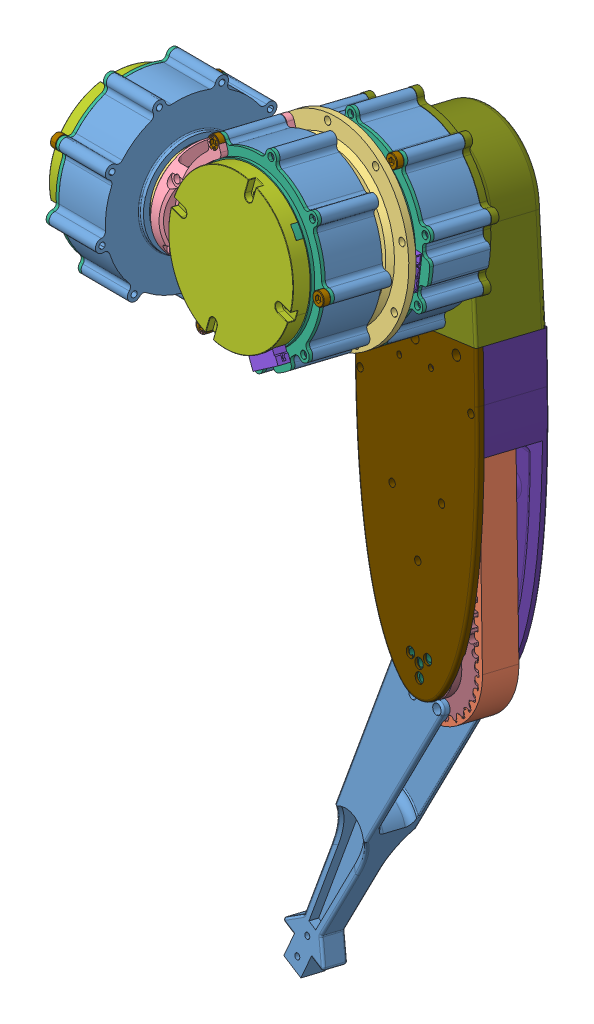
SolidWorks assembly 左后机械腿装配体, configuration 默认. Lengths in mm.
Overall size (159.19 372.62 150.59).
74 component instances, 22 part files, 38 mates.
Components (placement in the parent):
- CyberGearmotor.stp-1: CyberGearmotor.stp [默认] at (-142.9677 146.7561 185.5962) x (0.968253 -0.203796 0.14475) z (-0.114976 0.151089 0.981811) size (96.28 96.17 36.5)
  - ASM0002_ASM_1_ASM.stp-1: ASM0002_ASM_1_ASM.stp [默认] at origin size (96.28 96.17 36.5)
    - ASM0002_ASM_1_ASM_1_ASM.stp-1: ASM0002_ASM_1_ASM_1_ASM.stp [默认] at origin size (96.28 96.17 36.5)
      - 0714_ASM_1_ASM_1_ASM_1_ASM.stp-1: 0714_ASM_1_ASM_1_ASM_1_ASM.stp [默认] at origin size (96.28 96.17 36.5)
        - 3_1_02_067_0003_ASM_ASM_1_ASM_1_ASM.stp-1: 3_1_02_067_0003_ASM_ASM_1_ASM_1_ASM.stp [默认] at origin size (96.28 96.17 36.5)
          - 3_1_02_067_0003_ASM_1_ASM_1_ASM_ASM.stp-1: 3_1_02_067_0003_ASM_1_ASM_1_ASM_ASM.stp [默认] at origin size (96.28 96.17 36.5)
            - 1_1_06_EB673-504_1_1_1_1_1.stp-1: 1_1_06_EB673-504_1_1_1_1_1.stp [默认] at (39.8324 39.833 -22) size (79.19 78.95 25.5)
            - 1_2_04_670601_1_1_1_1_1.stp-1: 1_2_04_670601_1_1_1_1_1.stp [默认] at (93.9161 79.9966 -44) size (37 37 4)
            - 1_1_02_EB671-500_1_1_1_1_1.stp-1: 1_1_02_EB671-500_1_1_1_1_1.stp [默认] at (93.9161 79.9966 -44.4) x (-0.960973 0.276644 0) z (0 0 1) size (33 33 8.5)
            - 1_2_04_694000_1_1_1_1_1.stp-1: 1_2_04_694000_1_1_1_1_1.stp [默认] at (93.9161 79.9966 -44.5) size (11 11 4)
            - 1_2_06_000213_1_1_1_1_1.stp-1: 1_2_06_000213_1_1_1_1_1.stp [默认] at (93.9161 79.9966 -45.5) size (38.8 36.2 1.5)
            - 1_1_31_QT-642_1_1_1_1_1.stp-1: 1_1_31_QT-642_1_1_1_1_1.stp [默认] at (93.9161 79.9966 -22) x (-0.970555 -0.24088 0) z (0 0 -1) size (79.5 79.36 6)
            - 1_1_06_EB673-502_1_1_1_1_1.stp-1: 1_1_06_EB673-502_1_1_1_1_1.stp [默认] at (93.9161 79.9966 -13) x (-0.515958 -0.856614 0) z (0 0 -1) size (63 63 8)
          - 0518_ASM_2_ASM_1_ASM_1_ASM_1_AS_ASM.stp-1: 0518_ASM_2_ASM_1_ASM_1_ASM_1_AS_ASM.stp [默认] at (93.9161 79.9966 -17.235) x (0.235897 -0.971778 0) z (0 0 1) size (15.5 11.3 5.2)
            - 12345_ASM_1_ASM_2_ASM_1_ASM_1_A_ASM.stp-1: 12345_ASM_1_ASM_2_ASM_1_ASM_1_A_ASM.stp [默认] at origin size (15.5 11.3 5.2)
              - DUANZI_1_3_1_1_1_1_1_1.stp-1: DUANZI_1_3_1_1_1_1_1_1.stp [默认] at (-0.1798 16.5474 0.4329) x (0 0 -1) z (0 1 0) size (5.2 15.5 11.3)
      - LUODING_1_1.stp-1: LUODING_1_1.stp [默认] at (119.9375 52.9941 -20.5) x (-1 0 0) z (0 1 0) size (5.68 3 5.68)
      - LUODING_1_1.stp-2: LUODING_1_1.stp [默认] at (104.2902 116.0331 -20.5) x (-1 0 0) z (0 1 0) size (5.68 3 5.68)
      - LUODING_1_1.stp-3: LUODING_1_1.stp [默认] at (57.5205 70.9626 -20.5) x (-1 0 0) z (0 1 0) size (5.68 3 5.68)
  - 0411-2_4_1_3_1.stp-1: 0411-2_4_1_3_1.stp [默认] at (93.9161 79.9964 -17.5) x (0.235904 -0.971776 0) z (0 0 1) size (58 56.68 1.62)
- 带轮-1: 带轮 [默认] at (-26.5163 194.7974 123.0899) x (-0.682793 -0.729895 0.032363) z (-0.114976 0.151089 0.981811) size (43.22 43.22 15)
- 带轮挡边-1: 带轮挡边 [默认] at (-28.2409 197.0638 137.8171) x (-0.682793 -0.729895 0.032363) z (-0.114976 0.151089 0.981811) size (50 50 4)
- 带轮挡边-2: 带轮挡边 [默认] at (-26.0564 194.1931 119.1627) x (-0.432175 0.882318 -0.186388) z (-0.114976 0.151089 0.981811) size (50 50 4)
- 膝关节带轮-1: 膝关节带轮 [默认] at (-17.7229 50.8623 146.2695) x (-0.93026 0.33029 -0.159767) z (-0.114976 0.151089 0.981811) size (43.22 43.22 23)
- 轴承-1: 轴承 [默认] at (0.7633 46.7268 167.9135) x (-0.724883 0.663028 -0.18692) z (0.114976 -0.151089 -0.981811) size (23 23 4)
- 轴承-2: 轴承 [默认] at (2.8904 43.9316 149.75) x (0.870598 0.491289 0.026349) z (0.114976 -0.151089 -0.981811) size (23 23 4)
- 膝关节转轴-1: 膝关节转轴 [默认] at (0.4759 47.1045 170.368) x (-0.717392 0.671027 -0.187274) z (0.114976 -0.151089 -0.981811) size (21 21 29)
- 大腿根部SLDPRT-3: 大腿根部SLDPRT [默认] at (-72.9613 257.7727 130.3673) x (0.051984 0.987926 -0.145942) z (0.114976 -0.151089 -0.981811) size (94.61 80.08 30.19)
- 大腿前部-1: 大腿前部 [默认] at (-3.2719 120.5903 129.0833) x (0.975319 0.204724 0.082711) z (0.188504 -0.967088 0.170898) size (62 27.01 128.98)
- 大腿前部盖子-1: 大腿前部盖子 [默认] at (-22.2764 121.8579 157.2185) x (-0.975319 -0.204724 -0.082711) z (0.188504 -0.967088 0.170898) size (62 3.5 129)
- 小腿2-1: 小腿2 [默认] at (-21.3684 -15.2067 168.7414) x (-0.348421 -0.931709 0.102576) z (0.93026 -0.33029 0.159767) size (141.69 21.45 28.63)
- 5m同步带1-1: 5m同步带1 [默认] at (1.8414 46.0222 156.9444) x (0.114976 -0.151089 -0.981811) z (0.188504 -0.967088 0.170898) size (15 46.9 201.91)
- 连接盘-1: 连接盘 [默认] at (-34.1913 204.3072 182.3485) x (-0.085987 0.983142 -0.161363) z (-0.98964 -0.102976 -0.100046) size (80.5 13.5 80.5)
- CyberGearmotor.stp-2: CyberGearmotor.stp [默认] at (-146.2904 268.3897 208.758) x (0.350014 -0.918818 0.182384) z (-0.114976 0.151089 0.981811) size (96.28 96.17 36.5)
  - ASM0002_ASM_1_ASM.stp-1: ASM0002_ASM_1_ASM.stp [默认] at origin size (96.28 96.17 36.5)
    - ASM0002_ASM_1_ASM_1_ASM.stp-1: ASM0002_ASM_1_ASM_1_ASM.stp [默认] at origin size (96.28 96.17 36.5)
      - 0714_ASM_1_ASM_1_ASM_1_ASM.stp-1: 0714_ASM_1_ASM_1_ASM_1_ASM.stp [默认] at origin size (96.28 96.17 36.5)
        - 3_1_02_067_0003_ASM_ASM_1_ASM_1_ASM.stp-1: 3_1_02_067_0003_ASM_ASM_1_ASM_1_ASM.stp [默认] at origin size (96.28 96.17 36.5)
          - 3_1_02_067_0003_ASM_1_ASM_1_ASM_ASM.stp-1: 3_1_02_067_0003_ASM_1_ASM_1_ASM_ASM.stp [默认] at origin size (96.28 96.17 36.5)
            - 1_1_06_EB673-504_1_1_1_1_1.stp-1: 1_1_06_EB673-504_1_1_1_1_1.stp [默认] at (39.8324 39.833 -22) size (79.19 78.95 25.5)
            - 1_2_04_670601_1_1_1_1_1.stp-1: 1_2_04_670601_1_1_1_1_1.stp [默认] at (93.9161 79.9966 -44) size (37 37 4)
            - 1_1_02_EB671-500_1_1_1_1_1.stp-1: 1_1_02_EB671-500_1_1_1_1_1.stp [默认] at (93.9161 79.9966 -44.4) x (-0.960973 0.276644 0) z (0 0 1) size (33 33 8.5)
            - 1_2_04_694000_1_1_1_1_1.stp-1: 1_2_04_694000_1_1_1_1_1.stp [默认] at (93.9161 79.9966 -44.5) size (11 11 4)
            - 1_2_06_000213_1_1_1_1_1.stp-1: 1_2_06_000213_1_1_1_1_1.stp [默认] at (93.9161 79.9966 -45.5) size (38.8 36.2 1.5)
            - 1_1_31_QT-642_1_1_1_1_1.stp-1: 1_1_31_QT-642_1_1_1_1_1.stp [默认] at (93.9161 79.9966 -22) x (-0.970555 -0.24088 0) z (0 0 -1) size (79.5 79.36 6)
            - 1_1_06_EB673-502_1_1_1_1_1.stp-1: 1_1_06_EB673-502_1_1_1_1_1.stp [默认] at (93.9161 79.9966 -13) x (-0.515958 -0.856614 0) z (0 0 -1) size (63 63 8)
          - 0518_ASM_2_ASM_1_ASM_1_ASM_1_AS_ASM.stp-1: 0518_ASM_2_ASM_1_ASM_1_ASM_1_AS_ASM.stp [默认] at (93.9161 79.9966 -17.235) x (0.235897 -0.971778 0) z (0 0 1) size (15.5 11.3 5.2)
            - 12345_ASM_1_ASM_2_ASM_1_ASM_1_A_ASM.stp-1: 12345_ASM_1_ASM_2_ASM_1_ASM_1_A_ASM.stp [默认] at origin size (15.5 11.3 5.2)
              - DUANZI_1_3_1_1_1_1_1_1.stp-1: DUANZI_1_3_1_1_1_1_1_1.stp [默认] at (-0.1798 16.5474 0.4329) x (0 0 -1) z (0 1 0) size (5.2 15.5 11.3)
      - LUODING_1_1.stp-1: LUODING_1_1.stp [默认] at (119.9375 52.9941 -20.5) x (-1 0 0) z (0 1 0) size (5.68 3 5.68)
      - LUODING_1_1.stp-2: LUODING_1_1.stp [默认] at (104.2902 116.0331 -20.5) x (-1 0 0) z (0 1 0) size (5.68 3 5.68)
      - LUODING_1_1.stp-3: LUODING_1_1.stp [默认] at (57.5205 70.9626 -20.5) x (-1 0 0) z (0 1 0) size (5.68 3 5.68)
  - 0411-2_4_1_3_1.stp-1: 0411-2_4_1_3_1.stp [默认] at (93.9161 79.9964 -17.5) x (0.235904 -0.971776 0) z (0 0 1) size (58 56.68 1.62)
- 肩关节连接器-1: 肩关节连接器 [默认] at (-42.6517 134.7106 191.8641) x (0.350039 -0.918808 0.182385) z (-0.929652 -0.364642 -0.052754) size (67.92 36.71 40.7)
- CyberGearmotor.stp-3: CyberGearmotor.stp [默认] at (-142.1543 303.9583 248.4574) x (0.127941 -0.335558 -0.933291) z (-0.990208 -0.096202 -0.101155) size (96.28 96.17 36.5)
  - ASM0002_ASM_1_ASM.stp-1: ASM0002_ASM_1_ASM.stp [默认] at origin size (96.28 96.17 36.5)
    - ASM0002_ASM_1_ASM_1_ASM.stp-1: ASM0002_ASM_1_ASM_1_ASM.stp [默认] at origin size (96.28 96.17 36.5)
      - 0714_ASM_1_ASM_1_ASM_1_ASM.stp-1: 0714_ASM_1_ASM_1_ASM_1_ASM.stp [默认] at origin size (96.28 96.17 36.5)
        - 3_1_02_067_0003_ASM_ASM_1_ASM_1_ASM.stp-1: 3_1_02_067_0003_ASM_ASM_1_ASM_1_ASM.stp [默认] at origin size (96.28 96.17 36.5)
          - 3_1_02_067_0003_ASM_1_ASM_1_ASM_ASM.stp-1: 3_1_02_067_0003_ASM_1_ASM_1_ASM_ASM.stp [默认] at origin size (96.28 96.17 36.5)
            - 1_1_06_EB673-504_1_1_1_1_1.stp-1: 1_1_06_EB673-504_1_1_1_1_1.stp [默认] at (39.8324 39.833 -22) size (79.19 78.95 25.5)
            - 1_2_04_670601_1_1_1_1_1.stp-1: 1_2_04_670601_1_1_1_1_1.stp [默认] at (93.9161 79.9966 -44) size (37 37 4)
            - 1_1_02_EB671-500_1_1_1_1_1.stp-1: 1_1_02_EB671-500_1_1_1_1_1.stp [默认] at (93.9161 79.9966 -44.4) x (-0.960973 0.276644 0) z (0 0 1) size (33 33 8.5)
            - 1_2_04_694000_1_1_1_1_1.stp-1: 1_2_04_694000_1_1_1_1_1.stp [默认] at (93.9161 79.9966 -44.5) size (11 11 4)
            - 1_2_06_000213_1_1_1_1_1.stp-1: 1_2_06_000213_1_1_1_1_1.stp [默认] at (93.9161 79.9966 -45.5) size (38.8 36.2 1.5)
            - 1_1_31_QT-642_1_1_1_1_1.stp-1: 1_1_31_QT-642_1_1_1_1_1.stp [默认] at (93.9161 79.9966 -22) x (-0.970555 -0.24088 0) z (0 0 -1) size (79.5 79.36 6)
            - 1_1_06_EB673-502_1_1_1_1_1.stp-1: 1_1_06_EB673-502_1_1_1_1_1.stp [默认] at (93.9161 79.9966 -13) x (-0.515958 -0.856614 0) z (0 0 -1) size (63 63 8)
          - 0518_ASM_2_ASM_1_ASM_1_ASM_1_AS_ASM.stp-1: 0518_ASM_2_ASM_1_ASM_1_ASM_1_AS_ASM.stp [默认] at (93.9161 79.9966 -17.235) x (0.235897 -0.971778 0) z (0 0 1) size (15.5 11.3 5.2)
            - 12345_ASM_1_ASM_2_ASM_1_ASM_1_A_ASM.stp-1: 12345_ASM_1_ASM_2_ASM_1_ASM_1_A_ASM.stp [默认] at origin size (15.5 11.3 5.2)
              - DUANZI_1_3_1_1_1_1_1_1.stp-1: DUANZI_1_3_1_1_1_1_1_1.stp [默认] at (-0.1798 16.5474 0.4329) x (0 0 -1) z (0 1 0) size (5.2 15.5 11.3)
      - LUODING_1_1.stp-1: LUODING_1_1.stp [默认] at (119.9375 52.9941 -20.5) x (-1 0 0) z (0 1 0) size (5.68 3 5.68)
      - LUODING_1_1.stp-2: LUODING_1_1.stp [默认] at (104.2902 116.0331 -20.5) x (-1 0 0) z (0 1 0) size (5.68 3 5.68)
      - LUODING_1_1.stp-3: LUODING_1_1.stp [默认] at (57.5205 70.9626 -20.5) x (-1 0 0) z (0 1 0) size (5.68 3 5.68)
  - 0411-2_4_1_3_1.stp-1: 0411-2_4_1_3_1.stp [默认] at (93.9161 79.9964 -17.5) x (0.235904 -0.971776 0) z (0 0 1) size (58 56.68 1.62)
Mates (geometry in assembly coordinates):
- 同心1: concentric aligned: cylinder of CyberGearmotor.stp-1/ASM0002_ASM_1_ASM.stp-1/ASM0002_ASM_1_ASM_1_ASM.stp-1/0714_ASM_1_ASM_1_ASM_1_ASM.stp-1/3_1_02_067_0003_ASM_ASM_1_ASM_1_ASM.stp-1/3_1_02_067_0003_ASM_1_ASM_1_ASM_ASM.stp-1/1_1_02_EB671-500_1_1_1_1_1.stp-1 through (-29.1722 198.2876 145.7697) axis (0.114976 -0.151089 -0.981811) radius 16.5; cylinder of 带轮挡边-1 through (-28.7008 197.6681 141.7443) axis (0.114976 -0.151089 -0.981811) radius 25
- 重合1: coincident anti-aligned: plane of CyberGearmotor.stp-1/ASM0002_ASM_1_ASM.stp-1/ASM0002_ASM_1_ASM_1_ASM.stp-1/0714_ASM_1_ASM_1_ASM_1_ASM.stp-1/3_1_02_067_0003_ASM_ASM_1_ASM_1_ASM.stp-1/3_1_02_067_0003_ASM_1_ASM_1_ASM_ASM.stp-1/1_1_02_EB671-500_1_1_1_1_1.stp-1 through (-28.7008 197.6681 141.7443) normal (0.114976 -0.151089 -0.981811); plane of 带轮挡边-1 through (-28.7008 197.6681 141.7443) normal (-0.114976 0.151089 0.981811)
- 重合4: coincident anti-aligned: plane of 带轮-1 through (-14.8718 181.0807 141.8423) normal (-0.114976 0.151089 0.981811); plane of 带轮挡边-1 through (-28.2409 197.0638 137.8171) normal (0.114976 -0.151089 -0.981811)
- 同心12: concentric aligned: cylinder of CyberGearmotor.stp-1/ASM0002_ASM_1_ASM.stp-1/ASM0002_ASM_1_ASM_1_ASM.stp-1/0714_ASM_1_ASM_1_ASM_1_ASM.stp-1/3_1_02_067_0003_ASM_ASM_1_ASM_1_ASM.stp-1/3_1_02_067_0003_ASM_1_ASM_1_ASM_ASM.stp-1/1_1_02_EB671-500_1_1_1_1_1.stp-1 through (-29.1722 198.2876 145.7697) axis (0.114976 -0.151089 -0.981811) radius 16.5; cylinder of 带轮挡边-2 through (-26.5163 194.7974 123.0899) axis (0.114976 -0.151089 -0.981811) radius 25
- 重合5: coincident anti-aligned: plane of 带轮-1 through (-13.1472 178.8144 127.1151) normal (0.114976 -0.151089 -0.981811); plane of 带轮挡边-2 through (-26.5163 194.7974 123.0899) normal (-0.114976 0.151089 0.981811)
- 同心20: concentric aligned: cylinder of 轴承-1 through (1.2232 46.1224 163.9863) axis (-0.114976 0.151089 0.981811) radius 8.5; cylinder of 膝关节转轴-1 through (3.6952 42.874 142.8773) axis (-0.114976 0.151089 0.981811) radius 8.5
- 重合12: coincident anti-aligned: plane of CyberGearmotor.stp-1/ASM0002_ASM_1_ASM.stp-1/ASM0002_ASM_1_ASM_1_ASM.stp-1/0714_ASM_1_ASM_1_ASM_1_ASM.stp-1/3_1_02_067_0003_ASM_ASM_1_ASM_1_ASM.stp-1/3_1_02_067_0003_ASM_1_ASM_1_ASM_ASM.stp-1/1_1_06_EB673-504_1_1_1_1_1.stp-1 through (-28.7634 197.364 144.8394) normal (0.114976 -0.151089 -0.981811); plane of 大腿根部SLDPRT-3 through (-72.9613 257.7727 130.3673) normal (-0.114976 0.151089 0.981811)
- 重合17: coincident anti-aligned: plane of 大腿根部SLDPRT-3 through (-47.5354 139.1765 124.0952) normal (0.114976 -0.151089 -0.981811); plane of 大腿前部-1 through (-3.6168 121.0436 132.0288) normal (-0.114976 0.151089 0.981811)
- 重合18: coincident anti-aligned: plane of 大腿根部SLDPRT-3 through (-52.5248 152.9267 148.8951) normal (0.188504 -0.967088 0.170898); plane of 大腿前部-1 through (-10.6236 156.991 125.6764) normal (-0.188504 0.967088 -0.170898)
- 重合21: coincident anti-aligned: plane of 大腿根部SLDPRT-3 through (7.6884 155.4992 155.5506) normal (0.975319 0.204724 0.082711); plane of 大腿前部-1 through (13.1551 128.7695 157.2486) normal (-0.975319 -0.204724 -0.082711)
- 同心32: concentric anti-aligned: cylinder of 膝关节转轴-1 through (3.6952 42.874 142.8773) axis (-0.114976 0.151089 0.981811) radius 8.5; cylinder of 大腿前部-1 through (3.4652 43.1762 144.841) axis (0.114976 -0.151089 -0.981811) radius 8.5
- 重合23: coincident aligned: plane of 膝关节转轴-1 through (3.8102 42.7229 141.8955) normal (0.114976 -0.151089 -0.981811); plane of 大腿前部-1 through (-3.2719 120.5903 129.0833) normal (0.114976 -0.151089 -0.981811)
- 重合32: coincident anti-aligned: plane of 带轮挡边-1 through (-28.2409 197.0638 137.8171) normal (0.114976 -0.151089 -0.981811); plane of 5m同步带1-1 through (-18.184 43.133 162.6829) normal (-0.114976 0.151089 0.981811)
- 同心44: concentric aligned: cylinder of 带轮挡边-1 through (-28.7008 197.6681 141.7443) axis (0.114976 -0.151089 -0.981811) radius 25; cylinder of 5m同步带1-1 through (-27.3786 195.9306 130.4535) axis (0.114976 -0.151089 -0.981811) radius 23.448
- 同心47: concentric anti-aligned: cylinder of 膝关节带轮-1 through (1.1657 46.198 164.4772) axis (0.114976 -0.151089 -0.981811) radius 10.5; cylinder of 膝关节转轴-1 through (3.6952 42.874 142.8773) axis (-0.114976 0.151089 0.981811) radius 8.5
- 重合36: coincident anti-aligned: plane of 膝关节带轮-1 through (-6.9366 25.2381 151.4759) normal (0.114976 -0.151089 -0.981811); plane of 轴承-2 through (2.8904 43.9316 149.75) normal (-0.114976 0.151089 0.981811)
- 重合38: coincident anti-aligned: plane of 带轮-1 through (-14.8718 181.0807 141.8423) normal (-0.114976 0.151089 0.981811); plane of 带轮挡边-1 through (-28.2409 197.0638 137.8171) normal (0.114976 -0.151089 -0.981811)
- 重合39: coincident aligned: plane of 带轮-1 through (-13.1472 178.8144 127.1151) normal (0.114976 -0.151089 -0.981811); plane of 膝关节带轮-1 through (-6.9366 25.2381 151.4759) normal (0.114976 -0.151089 -0.981811)
- 重合41: coincident anti-aligned: plane of 膝关节带轮-1 through (1.2063 46.067 163.9928) normal (-0.114976 0.151089 0.981811); plane of 轴承-1 through (1.2232 46.1224 163.9863) normal (0.114976 -0.151089 -0.981811)
- 重合42: coincident anti-aligned: plane of 膝关节带轮-1 through (-6.9366 25.2381 151.4759) normal (0.114976 -0.151089 -0.981811); plane of 小腿2-1 through (-19.9312 -17.0953 156.4688) normal (-0.114976 0.151089 0.981811)
- 同心50: concentric aligned: cylinder of 膝关节带轮-1 through (7.7485 31.9201 167.4453) axis (-0.114976 0.151089 0.981811) radius 1.65; cylinder of 小腿2-1 through (13.1523 24.8189 121.3001) axis (-0.114976 0.151089 0.981811) radius 2.1
- 同心51: concentric aligned: cylinder of 膝关节带轮-1 through (-4.409 31.2906 166.1184) axis (-0.114976 0.151089 0.981811) radius 1.65; cylinder of 小腿2-1 through (0.9949 24.1895 119.9733) axis (-0.114976 0.151089 0.981811) radius 2.1
- 同心53: concentric aligned: circle of 轴承-2; cylinder of 膝关节转轴-1 through (1.0507 46.3491 165.459) axis (0.114976 -0.151089 -0.981811) radius 7
- 重合44: coincident anti-aligned: plane of 大腿根部SLDPRT-3 through (-50.2949 142.8026 147.6587) normal (-0.114976 0.151089 0.981811); plane of 大腿前部盖子-1 through (-21.9314 121.4046 154.2731) normal (0.114976 -0.151089 -0.981811)
- 同心54: concentric anti-aligned: cylinder of 大腿根部SLDPRT-3 through (-37.9404 146.2238 124.1343) axis (0.114976 -0.151089 -0.981811) radius 1.65; cylinder of 大腿前部盖子-1 through (-40.6998 149.8499 147.6978) axis (-0.114976 0.151089 0.981811) radius 2.1
- 同心55: concentric anti-aligned: cylinder of 大腿根部SLDPRT-3 through (3.023 154.8222 127.6082) axis (0.114976 -0.151089 -0.981811) radius 1.65; cylinder of 大腿前部盖子-1 through (0.2636 158.4484 151.1717) axis (-0.114976 0.151089 0.981811) radius 2.1
- 重合45: coincident anti-aligned: plane of CyberGearmotor.stp-1/ASM0002_ASM_1_ASM.stp-1/ASM0002_ASM_1_ASM_1_ASM.stp-1/0714_ASM_1_ASM_1_ASM_1_ASM.stp-1/3_1_02_067_0003_ASM_ASM_1_ASM_1_ASM.stp-1/3_1_02_067_0003_ASM_1_ASM_1_ASM_ASM.stp-1/1_1_06_EB673-502_1_1_1_1_1.stp-1 through (-32.8974 203.1829 177.5804) normal (-0.114976 0.151089 0.981811); plane of 连接盘-1 through (-33.6164 203.5518 177.4394) normal (0.114976 -0.151089 -0.981811)
- 同心56: concentric aligned: cylinder of CyberGearmotor.stp-1/ASM0002_ASM_1_ASM.stp-1/ASM0002_ASM_1_ASM_1_ASM.stp-1/0714_ASM_1_ASM_1_ASM_1_ASM.stp-1/3_1_02_067_0003_ASM_ASM_1_ASM_1_ASM.stp-1/3_1_02_067_0003_ASM_1_ASM_1_ASM_ASM.stp-1/1_1_06_EB673-502_1_1_1_1_1.stp-1 through (-31.9776 201.9741 169.7259) axis (-0.114976 0.151089 0.981811) radius 31.5; cylinder of 连接盘-1 through (-32.8974 203.1829 177.5804) axis (-0.114976 0.151089 0.981811) radius 40.25
- 同心57: concentric aligned: cylinder of CyberGearmotor.stp-1/ASM0002_ASM_1_ASM.stp-1/ASM0002_ASM_1_ASM_1_ASM.stp-1/0714_ASM_1_ASM_1_ASM_1_ASM.stp-1/3_1_02_067_0003_ASM_ASM_1_ASM_1_ASM.stp-1/3_1_02_067_0003_ASM_1_ASM_1_ASM_ASM.stp-1/1_1_31_QT-642_1_1_1_1_1.stp-1 through (-60.0224 177.0746 169.7642) axis (-0.114976 0.151089 0.981811) radius 1.55; cylinder of 连接盘-1 through (-60.9997 178.3588 178.1096) axis (-0.114976 0.151089 0.981811) radius 1.6
- 同心61: concentric aligned: cylinder of CyberGearmotor.stp-1/ASM0002_ASM_1_ASM.stp-1/ASM0002_ASM_1_ASM_1_ASM.stp-1/0714_ASM_1_ASM_1_ASM_1_ASM.stp-1/3_1_02_067_0003_ASM_ASM_1_ASM_1_ASM.stp-1/3_1_02_067_0003_ASM_1_ASM_1_ASM_ASM.stp-1/1_1_06_EB673-502_1_1_1_1_1.stp-1 through (-31.9776 201.9741 169.7259) axis (-0.114976 0.151089 0.981811) radius 31.5; cylinder of CyberGearmotor.stp-2/ASM0002_ASM_1_ASM.stp-1/ASM0002_ASM_1_ASM_1_ASM.stp-1/0714_ASM_1_ASM_1_ASM_1_ASM.stp-1/3_1_02_067_0003_ASM_ASM_1_ASM_1_ASM.stp-1/3_1_02_067_0003_ASM_1_ASM_1_ASM_ASM.stp-1/1_1_06_EB673-502_1_1_1_1_1.stp-1 through (-36.7491 208.2443 210.4711) axis (-0.114976 0.151089 0.981811) radius 31.5
- 重合48: coincident anti-aligned: plane of 连接盘-1 through (-34.1913 204.3072 182.3485) normal (-0.114976 0.151089 0.981811); plane of CyberGearmotor.stp-2/ASM0002_ASM_1_ASM.stp-1/ASM0002_ASM_1_ASM_1_ASM.stp-1/0714_ASM_1_ASM_1_ASM_1_ASM.stp-1/3_1_02_067_0003_ASM_ASM_1_ASM_1_ASM.stp-1/3_1_02_067_0003_ASM_1_ASM_1_ASM_ASM.stp-1/1_1_02_EB671-500_1_1_1_1_1.stp-1 through (-33.4723 203.9383 182.4895) normal (0.114976 -0.151089 -0.981811)
- 同心70: concentric anti-aligned: cylinder of CyberGearmotor.stp-2/ASM0002_ASM_1_ASM.stp-1/ASM0002_ASM_1_ASM_1_ASM.stp-1/0714_ASM_1_ASM_1_ASM_1_ASM.stp-1/3_1_02_067_0003_ASM_ASM_1_ASM_1_ASM.stp-1/3_1_02_067_0003_ASM_1_ASM_1_ASM_ASM.stp-1/1_1_31_QT-642_1_1_1_1_1.stp-1 through (-36.6917 208.1688 209.9802) axis (-0.114976 0.151089 0.981811) radius 32; cylinder of 肩关节连接器-1 through (-37.0366 208.6221 212.9256) axis (0.114976 -0.151089 -0.981811) radius 32
- 重合51: coincident anti-aligned: plane of CyberGearmotor.stp-2/ASM0002_ASM_1_ASM.stp-1/ASM0002_ASM_1_ASM_1_ASM.stp-1/0714_ASM_1_ASM_1_ASM_1_ASM.stp-1/3_1_02_067_0003_ASM_ASM_1_ASM_1_ASM.stp-1/3_1_02_067_0003_ASM_1_ASM_1_ASM_ASM.stp-1/1_1_31_QT-642_1_1_1_1_1.stp-1 through (-36.6917 208.1688 209.9802) normal (-0.114976 0.151089 0.981811); plane of 肩关节连接器-1 through (-45.894 138.9713 219.5512) normal (0.114976 -0.151089 -0.981811)
- 同心71: concentric aligned: cylinder of CyberGearmotor.stp-2/ASM0002_ASM_1_ASM.stp-1/ASM0002_ASM_1_ASM_1_ASM.stp-1/0714_ASM_1_ASM_1_ASM_1_ASM.stp-1/3_1_02_067_0003_ASM_ASM_1_ASM_1_ASM.stp-1/3_1_02_067_0003_ASM_1_ASM_1_ASM_ASM.stp-1/1_1_06_EB673-504_1_1_1_1_1.stp-1 through (-72.4821 217.2415 203.3436) axis (0.114976 -0.151089 -0.981811) radius 1.25; cylinder of 肩关节连接器-1 through (-75.4519 221.1441 228.7038) axis (0.114976 -0.151089 -0.981811) radius 1.6
- 重合52: coincident anti-aligned: plane of 肩关节连接器-1 through (-70.3989 132.0149 189.0296) normal (-0.990208 -0.096202 -0.101155); plane of CyberGearmotor.stp-3/ASM0002_ASM_1_ASM.stp-1/ASM0002_ASM_1_ASM_1_ASM.stp-1/0714_ASM_1_ASM_1_ASM_1_ASM.stp-1/3_1_02_067_0003_ASM_ASM_1_ASM_1_ASM.stp-1/3_1_02_067_0003_ASM_1_ASM_1_ASM_ASM.stp-1/1_1_02_EB671-500_1_1_1_1_1.stp-1 through (-77.6463 202.1454 193.2776) normal (0.990208 0.096202 0.101155)
- 同心72: concentric anti-aligned: cylinder of 肩关节连接器-1 through (-32.5076 206.5308 197.8888) axis (-0.990208 -0.096202 -0.101155) radius 21; cylinder of CyberGearmotor.stp-3/ASM0002_ASM_1_ASM.stp-1/ASM0002_ASM_1_ASM_1_ASM.stp-1/0714_ASM_1_ASM_1_ASM_1_ASM.stp-1/3_1_02_067_0003_ASM_ASM_1_ASM_1_ASM.stp-1/3_1_02_067_0003_ASM_1_ASM_1_ASM_ASM.stp-1/1_1_02_EB671-500_1_1_1_1_1.stp-1 through (-81.7061 201.751 192.8629) axis (0.990208 0.096202 0.101155) radius 16.5
- 同心87: concentric aligned: cylinder of CyberGearmotor.stp-1/ASM0002_ASM_1_ASM.stp-1/ASM0002_ASM_1_ASM_1_ASM.stp-1/0714_ASM_1_ASM_1_ASM_1_ASM.stp-1/3_1_02_067_0003_ASM_ASM_1_ASM_1_ASM.stp-1/3_1_02_067_0003_ASM_1_ASM_1_ASM_ASM.stp-1/1_1_06_EB673-504_1_1_1_1_1.stp-1 through (-28.7975 197.7952 142.5701) axis (-0.114976 0.151089 0.981811) radius 21.5; cylinder of 大腿根部SLDPRT-3 through (-25.5965 193.5887 115.2354) axis (-0.114976 0.151089 0.981811) radius 29
- 平行1: parallel aligned: plane of 5m同步带1-1 through (-5.3716 201.8641 139.7565) normal (0.975319 0.204724 0.082711); plane of 大腿前部-1 through (18.8405 125.7575 133.9332) normal (0.975319 0.204724 0.082711)
